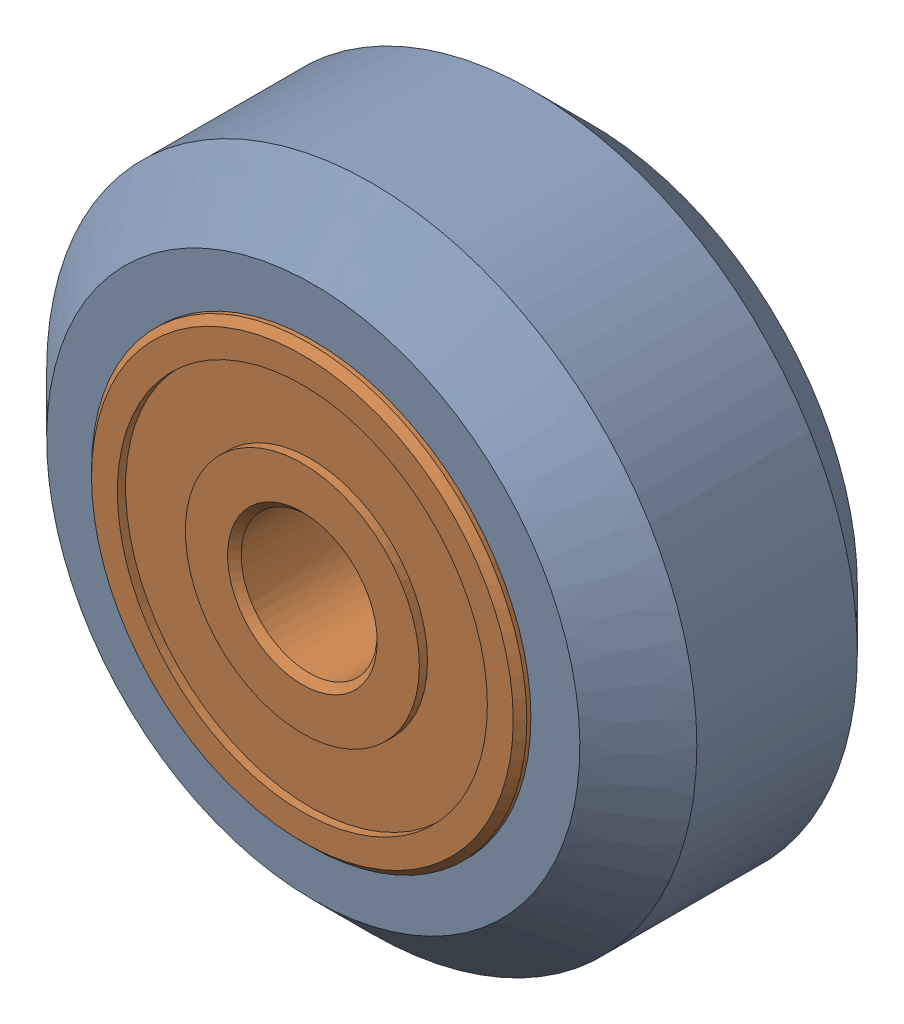
SolidWorks assembly Xtreme Solid V Wheel Assembly, configuration Default. Lengths in mm.
Overall size (23.9 23.9 11).
3 component instances, 2 part files, 0 mates.
Components (placement in the parent):
- Xtreme Solid V Wheel-1: Xtreme Solid V Wheel [Default] at (-45.15 -25 30) x (0 0 1) z (-1 0 0) size (10.2 23.9 23.9)
- Wheel+Kit+-+5x16x5mm+Sealed+Radial+Ball+Bearing.step.f3d-1: Wheel+Kit+-+5x16x5mm+Sealed+Radial+Ball+Bearing.step.f3d [Default] at (-45.15 -25 30) x (0 1 0) z (-1 0 0) size (16 5 16)
- Wheel+Kit+-+5x16x5mm+Sealed+Radial+Ball+Bearing.step.f3d-2: Wheel+Kit+-+5x16x5mm+Sealed+Radial+Ball+Bearing.step.f3d [Default] at (-45.15 -25 30) x (0 1 0) z (1 0 0) size (16 5 16)
